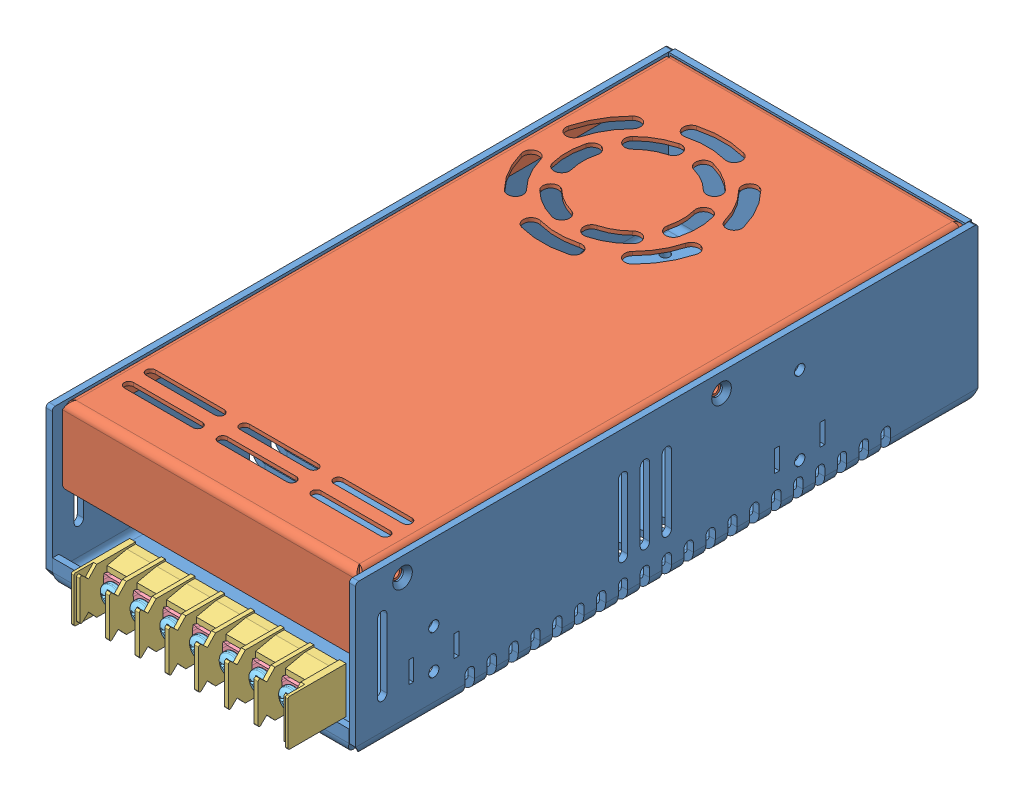
SolidWorks assembly Meanwell_SP-200-24, configuration Default. Lengths in mm.
Overall size (99.01 50.01 214.61).
24 component instances, 5 part files, 27 mates.
Components (placement in the parent):
- Meanwell_SP-200-24_Housing1-1: Meanwell_SP-200-24_Housing1 [Default] at origin size (99.01 49.51 199.32)
- Meanwell_SP-200-24_Housing2-1: Meanwell_SP-200-24_Housing2 [Default] at (0 46.8 -0.5) x (1 0 0) z (0 0 -1) size (94.84 24 194.01)
- Meanwell_SP-200-24_Terminal_Block-1: Meanwell_SP-200-24_Terminal_Block [Default] at (8.875 13.35 96.5) x (1 0 0) z (0 -1 0) size (69.25 18.6 14.7)
- Meanwell_Terminal_Screw-1: Meanwell_Terminal_Screw [Default] at (-19.75 13.35 106.9948) x (1 0 0) z (0 -1 0) size (8.4 8.8 8.4)
  - Clamp Plate Terminal Block-1: Clamp Plate Terminal Block [Default] at origin size (8.4 1.4 8.4)
  - Philips-Drive Panhead Screw Terminal Block-1: Philips-Drive Panhead Screw Terminal Block [92000A151] at (0 -6 0) x (1 0 0) z (0 1 0) size (7 7 8.8)
- Meanwell_Terminal_Screw-2: Meanwell_Terminal_Screw [Default] at (-10.25 13.35 106.9948) x (1 0 0) z (0 -1 0) size (8.4 8.8 8.4)
  - Clamp Plate Terminal Block-1: Clamp Plate Terminal Block [Default] at origin size (8.4 1.4 8.4)
  - Philips-Drive Panhead Screw Terminal Block-1: Philips-Drive Panhead Screw Terminal Block [92000A151] at (0 -6 0) x (1 0 0) z (0 1 0) size (7 7 8.8)
- Meanwell_Terminal_Screw-3: Meanwell_Terminal_Screw [Default] at (-0.75 13.35 106.9948) x (1 0 0) z (0 -1 0) size (8.4 8.8 8.4)
  - Clamp Plate Terminal Block-1: Clamp Plate Terminal Block [Default] at origin size (8.4 1.4 8.4)
  - Philips-Drive Panhead Screw Terminal Block-1: Philips-Drive Panhead Screw Terminal Block [92000A151] at (0 -6 0) x (1 0 0) z (0 1 0) size (7 7 8.8)
- Meanwell_Terminal_Screw-4: Meanwell_Terminal_Screw [Default] at (8.75 13.35 106.9948) x (1 0 0) z (0 -1 0) size (8.4 8.8 8.4)
  - Clamp Plate Terminal Block-1: Clamp Plate Terminal Block [Default] at origin size (8.4 1.4 8.4)
  - Philips-Drive Panhead Screw Terminal Block-1: Philips-Drive Panhead Screw Terminal Block [92000A151] at (0 -6 0) x (1 0 0) z (0 1 0) size (7 7 8.8)
- Meanwell_Terminal_Screw-5: Meanwell_Terminal_Screw [Default] at (18.25 13.35 106.9948) x (1 0 0) z (0 -1 0) size (8.4 8.8 8.4)
  - Clamp Plate Terminal Block-1: Clamp Plate Terminal Block [Default] at origin size (8.4 1.4 8.4)
  - Philips-Drive Panhead Screw Terminal Block-1: Philips-Drive Panhead Screw Terminal Block [92000A151] at (0 -6 0) x (1 0 0) z (0 1 0) size (7 7 8.8)
- Meanwell_Terminal_Screw-6: Meanwell_Terminal_Screw [Default] at (27.75 13.35 106.9948) x (1 0 0) z (0 -1 0) size (8.4 8.8 8.4)
  - Clamp Plate Terminal Block-1: Clamp Plate Terminal Block [Default] at origin size (8.4 1.4 8.4)
  - Philips-Drive Panhead Screw Terminal Block-1: Philips-Drive Panhead Screw Terminal Block [92000A151] at (0 -6 0) x (1 0 0) z (0 1 0) size (7 7 8.8)
- Meanwell_Terminal_Screw-7: Meanwell_Terminal_Screw [Default] at (37.25 13.35 106.9948) x (1 0 0) z (0 -1 0) size (8.4 8.8 8.4)
  - Clamp Plate Terminal Block-1: Clamp Plate Terminal Block [Default] at origin size (8.4 1.4 8.4)
  - Philips-Drive Panhead Screw Terminal Block-1: Philips-Drive Panhead Screw Terminal Block [92000A151] at (0 -6 0) x (1 0 0) z (0 1 0) size (7 7 8.8)
Mates (geometry in assembly coordinates):
- Coincident1: coincident aligned: plane of Meanwell_SP-200-24_Housing1-1 through (0 0 0) normal (1 0 0); plane of Meanwell_SP-200-24_Housing2-1
- Distance1: distance = 50 mm anti-aligned: plane of Meanwell_SP-200-24_Housing2-1 through (0 48 -0.5) normal (0 1 0); plane of Meanwell_SP-200-24_Housing1-1 through (0 -2 0) normal (0 -1 0)
- Coincident3: coincident anti-aligned: plane of Meanwell_SP-200-24_Housing1-1 through (0 0 -97.5) normal (0 0 1); plane of Meanwell_SP-200-24_Housing2-1 through (0 46.8 -97.5) normal (0 0 -1)
- Distance2: distance = 4 mm anti-aligned: plane of Meanwell_SP-200-24_Terminal_Block-1 through (43.5 13.35 96.5) normal (1 0 0); plane of Meanwell_SP-200-24_Housing1-1 through (47.5 0 0) normal (-1 0 0)
- Coincident5: coincident anti-aligned: plane of Meanwell_SP-200-24_Housing2-1 through (0 46.8 96.5) normal (0 0 1); plane of Meanwell_SP-200-24_Terminal_Block-1 through (43.5 6.6 96.5) normal (0 0 -1)
- Coincident6: coincident anti-aligned: plane of Meanwell_SP-200-24_Terminal_Block-1 through (42.65 6 114.6) normal (0 -1 0); plane of Meanwell_SP-200-24_Housing1-1 through (0 6 -99.506) normal (0 1 0)
- Concentric1: concentric anti-aligned: cylinder of Meanwell_SP-200-24_Terminal_Block-1 through (-19.75 13.35 105.6) axis (0 0 1) radius 1.45; cylinder of Meanwell_Terminal_Screw-1/Philips-Drive Panhead Screw Terminal Block-1 through (-19.75 13.35 100.9948) axis (0 0 -1) radius 3.5
- Coincident7: coincident: plane of Meanwell_SP-200-24_Terminal_Block-1 through (43.5 7.985 105.6) normal (0 0 1); point of Meanwell_Terminal_Screw-1/Clamp Plate Terminal Block-1
- Parallel1: parallel aligned: plane of Meanwell_SP-200-24_Terminal_Block-1 through (43.5 20.1 96.5) normal (0 1 0); plane of Meanwell_Terminal_Screw-1/Clamp Plate Terminal Block-1 through (-15.9 17.2 105.8248) normal (0 1 0)
- Concentric2: concentric anti-aligned: cylinder of Meanwell_SP-200-24_Terminal_Block-1 through (-10.25 13.35 105.6) axis (0 0 1) radius 1.45; cylinder of Meanwell_Terminal_Screw-2/Philips-Drive Panhead Screw Terminal Block-1 through (-10.25 13.35 100.9948) axis (0 0 -1) radius 3.5
- Concentric3: concentric anti-aligned: cylinder of Meanwell_SP-200-24_Terminal_Block-1 through (-0.75 13.35 105.6) axis (0 0 1) radius 1.45; cylinder of Meanwell_Terminal_Screw-3/Philips-Drive Panhead Screw Terminal Block-1 through (-0.75 13.35 100.9948) axis (0 0 -1) radius 3.5
- Concentric4: concentric anti-aligned: cylinder of Meanwell_SP-200-24_Terminal_Block-1 through (8.75 13.35 105.6) axis (0 0 1) radius 1.45; cylinder of Meanwell_Terminal_Screw-4/Philips-Drive Panhead Screw Terminal Block-1 through (8.75 13.35 100.9948) axis (0 0 -1) radius 3.5
- Concentric5: concentric anti-aligned: cylinder of Meanwell_SP-200-24_Terminal_Block-1 through (18.25 13.35 105.6) axis (0 0 1) radius 1.45; cylinder of Meanwell_Terminal_Screw-5/Philips-Drive Panhead Screw Terminal Block-1 through (18.25 13.35 100.9948) axis (0 0 -1) radius 3.5
- Concentric6: concentric anti-aligned: cylinder of Meanwell_SP-200-24_Terminal_Block-1 through (27.75 13.35 105.6) axis (0 0 1) radius 1.45; cylinder of Meanwell_Terminal_Screw-6/Philips-Drive Panhead Screw Terminal Block-1 through (27.75 13.35 100.9948) axis (0 0 -1) radius 3.5
- Concentric7: concentric anti-aligned: cylinder of Meanwell_SP-200-24_Terminal_Block-1 through (37.25 13.35 105.6) axis (0 0 1) radius 1.45; cylinder of Meanwell_Terminal_Screw-7/Philips-Drive Panhead Screw Terminal Block-1 through (37.25 13.35 100.9948) axis (0 0 -1) radius 3.5
- Parallel2: parallel aligned: plane of Meanwell_SP-200-24_Terminal_Block-1 through (43.5 20.1 96.5) normal (0 1 0); plane of Meanwell_Terminal_Screw-2/Clamp Plate Terminal Block-1 through (-6.4 17.2 105.8248) normal (0 1 0)
- Parallel3: parallel aligned: plane of Meanwell_SP-200-24_Terminal_Block-1 through (43.5 20.1 96.5) normal (0 1 0); plane of Meanwell_Terminal_Screw-3/Clamp Plate Terminal Block-1 through (3.1 17.2 105.8248) normal (0 1 0)
- Parallel4: parallel aligned: plane of Meanwell_SP-200-24_Terminal_Block-1 through (43.5 20.1 96.5) normal (0 1 0); plane of Meanwell_Terminal_Screw-4/Clamp Plate Terminal Block-1 through (12.6 17.2 105.8248) normal (0 1 0)
- Parallel5: parallel aligned: plane of Meanwell_SP-200-24_Terminal_Block-1 through (43.5 20.1 96.5) normal (0 1 0); plane of Meanwell_Terminal_Screw-5/Clamp Plate Terminal Block-1 through (22.1 17.2 105.8248) normal (0 1 0)
- Parallel6: parallel aligned: plane of Meanwell_SP-200-24_Terminal_Block-1 through (43.5 20.1 96.5) normal (0 1 0); plane of Meanwell_Terminal_Screw-6/Clamp Plate Terminal Block-1 through (31.6 17.2 105.8248) normal (0 1 0)
- Parallel7: parallel aligned: plane of Meanwell_SP-200-24_Terminal_Block-1 through (43.5 20.1 96.5) normal (0 1 0); plane of Meanwell_Terminal_Screw-7/Clamp Plate Terminal Block-1 through (41.1 17.2 105.8248) normal (0 1 0)
- Coincident15: coincident: plane of Meanwell_SP-200-24_Terminal_Block-1 through (43.5 7.985 105.6) normal (0 0 1); point of Meanwell_Terminal_Screw-2/Clamp Plate Terminal Block-1
- Coincident16: coincident: plane of Meanwell_SP-200-24_Terminal_Block-1 through (43.5 7.985 105.6) normal (0 0 1); point of Meanwell_Terminal_Screw-3/Clamp Plate Terminal Block-1
- Coincident17: coincident: plane of Meanwell_SP-200-24_Terminal_Block-1 through (43.5 7.985 105.6) normal (0 0 1); point of Meanwell_Terminal_Screw-4/Clamp Plate Terminal Block-1
- Coincident18: coincident: plane of Meanwell_SP-200-24_Terminal_Block-1 through (43.5 7.985 105.6) normal (0 0 1); point of Meanwell_Terminal_Screw-5/Clamp Plate Terminal Block-1
- Coincident19: coincident: plane of Meanwell_SP-200-24_Terminal_Block-1 through (43.5 7.985 105.6) normal (0 0 1); point of Meanwell_Terminal_Screw-6/Clamp Plate Terminal Block-1
- Coincident20: coincident: plane of Meanwell_SP-200-24_Terminal_Block-1 through (43.5 7.985 105.6) normal (0 0 1); point of Meanwell_Terminal_Screw-7/Clamp Plate Terminal Block-1
